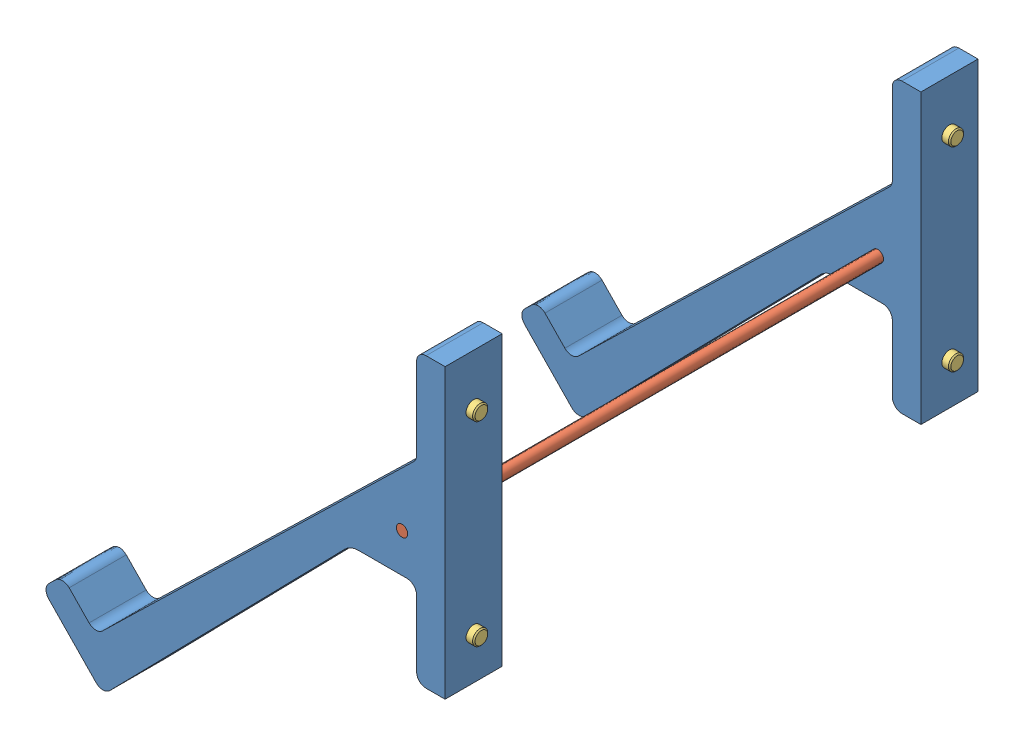
SolidWorks assembly minipcmural, configuration Défaut. Lengths in mm.
Overall size (213.75 237.01 280).
7 component instances, 3 part files, 9 mates.
Components (placement in the parent):
- portemurtal-1: portemurtal [Défaut] at (14.8994 72.5048 222.0067) size (209.7 237.01 30)
- portemurtal-2: portemurtal [Défaut] at (14.8994 72.5048 -27.9933) size (209.7 237.01 30)
- tigeinox6mm-1: tigeinox6mm [Défaut] at (7.2622 36.5479 0.9342) size (6 6 280)
- socket head cap screw_ai-1: socket head cap screw_ai [HX-SHCS 0.3125-24x0.75x0.75-N] at (6.9619 96.0618 -12.9933) size (26.99 11.91 11.91)
- socket head cap screw_ai-2: socket head cap screw_ai [HX-SHCS 0.3125-24x0.75x0.75-N] at (6.9619 96.0618 237.0067) size (26.99 11.91 11.91)
- socket head cap screw_ai-3: socket head cap screw_ai [HX-SHCS 0.3125-24x0.75x0.75-N] at (6.9619 -6.3376 -12.9933) size (26.99 11.91 11.91)
- socket head cap screw_ai-4: socket head cap screw_ai [HX-SHCS 0.3125-24x0.75x0.75-N] at (6.9619 -6.3376 237.0067) size (26.99 11.91 11.91)
Mates (geometry in assembly coordinates):
- Coaxiale1: concentric: cylinder of portemurtal-2 through (7.2622 36.5479 -27.9933) axis (0 0 1) radius 3; cylinder of tigeinox6mm-1 through (7.2622 36.5479 260.492) axis (0 0 -1) radius 3
- Coaxiale21: concentric: cylinder of portemurtal-2 through (44.8994 96.0618 -12.9933) axis (-1 0 0) radius 4; cylinder of socket head cap screw_ai-1 through (-24.7881 96.0618 -12.9933) axis (-1 0 0) radius 3.9688
- Coïncidente11: coincident: plane of portemurtal-2 through (14.8994 74.6189 2.0067) normal (-1 0 0); plane of socket head cap screw_ai-1 through (14.8994 102.0156 -12.9933) normal (1 0 0)
- Coaxiale31: concentric: cylinder of portemurtal-1 through (44.8994 96.0618 237.0067) axis (-1 0 0) radius 4; cylinder of socket head cap screw_ai-2 through (-24.7881 96.0618 237.0067) axis (-1 0 0) radius 3.9688
- Coïncidente21: coincident: plane of portemurtal-1 through (14.8994 74.6189 252.0067) normal (-1 0 0); plane of socket head cap screw_ai-2 through (14.8994 102.0156 237.0067) normal (1 0 0)
- Coaxiale41: concentric: cylinder of portemurtal-2 through (44.8994 -6.3376 -12.9933) axis (-1 0 0) radius 4; cylinder of socket head cap screw_ai-3 through (-24.7881 -6.3376 -12.9933) axis (-1 0 0) radius 3.9688
- Coïncidente31: coincident: plane of portemurtal-2 through (14.8994 21.1624 2.0067) normal (-1 0 0); plane of socket head cap screw_ai-3 through (14.8994 -0.3838 -12.9933) normal (1 0 0)
- Coaxiale51: concentric: cylinder of portemurtal-1 through (44.8994 -6.3376 237.0067) axis (-1 0 0) radius 4; cylinder of socket head cap screw_ai-4 through (-24.7881 -6.3376 237.0067) axis (-1 0 0) radius 3.9688
- Coïncidente41: coincident: plane of portemurtal-1 through (14.8994 21.1624 252.0067) normal (-1 0 0); plane of socket head cap screw_ai-4 through (14.8994 -0.3838 237.0067) normal (1 0 0)
